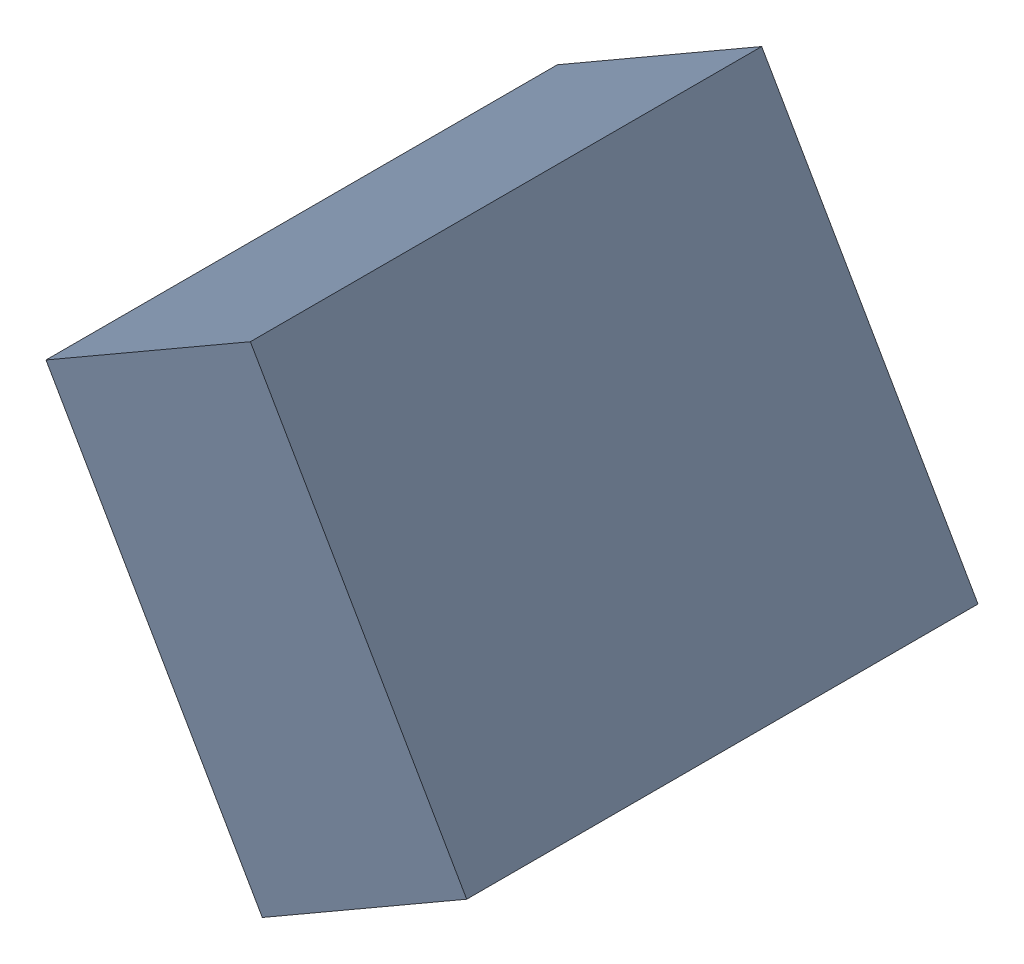
SolidWorks assembly C26_TDA5, configuration Standard. Lengths in mm.
Overall size (1.07 1.25 1.3).
2 component instances, 1 part files, 0 mates.
Components (placement in the parent):
- 885543192-1: 885543192 [Standard] at (-33.0721 -22.4933 0) size (1.07 1.25 1.3)
  - Extruded_27-1: Extruded_27 [Standard] at origin size (1.07 1.25 1.3)
